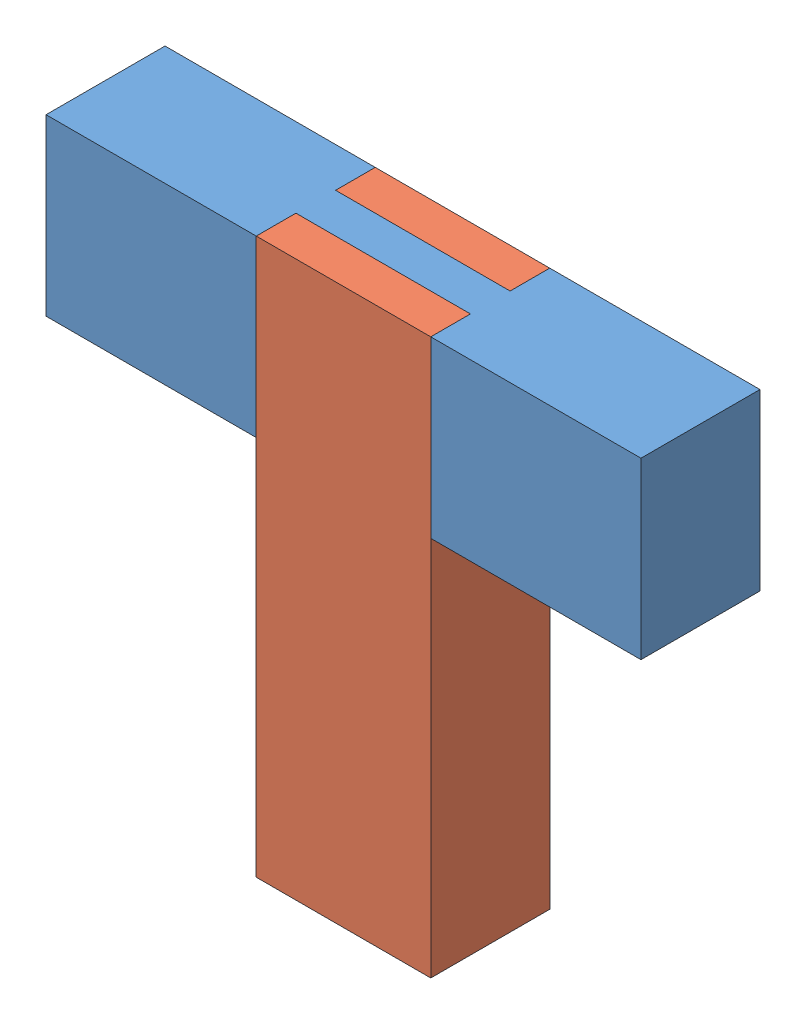
SolidWorks assembly BRIDLE ASSEM 2, configuration Default. Lengths in mm.
Overall size (150 140 30).
2 component instances, 2 part files, 3 mates.
Components (placement in the parent):
- PIECE B-1: PIECE B [Default] at (-65.926 62.5089 31.8072) size (150 44 30)
- PIECE A-2: PIECE A [Default] at (-12.926 -33.4911 31.8072) size (44 140 30)
Mates (geometry in assembly coordinates):
- Coincident1: coincident aligned: plane of PIECE B-1 through (-65.926 106.5089 61.8072) normal (0 1 0); plane of PIECE A-2 through (-12.926 106.5089 61.8072) normal (0 1 0)
- Coincident2: coincident aligned: plane of PIECE B-1 through (-65.926 106.5089 61.8072) normal (0 0 1); plane of PIECE A-2 through (-12.926 106.5089 61.8072) normal (0 0 1)
- Coincident3: coincident anti-aligned: plane of PIECE B-1 through (-12.926 106.5099 61.8072) normal (1 0 0); plane of PIECE A-2 through (-12.926 -33.4911 61.8072) normal (-1 0 0)
